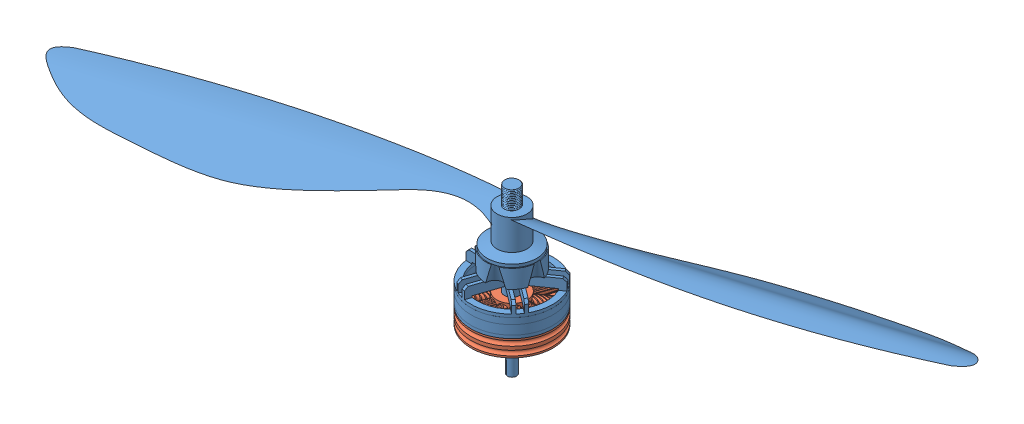
SolidWorks assembly Motordrone, configuration Predeterminado. Lengths in mm.
Overall size (2468.7 543.23 997.38).
2 component instances, 2 part files, 2 mates.
Components (placement in the parent):
- Motor drone-1: Motor drone [Predeterminado] at (-484.6905 198.3144 2500.6944) x (0.955281 0 -0.2957) z (0.2957 0 0.955281) size (2500.69 543.23 270)
- Pieza1-1: Pieza1 [Predeterminado] at (-484.6905 198.3144 2500.6944) x (-1 0 0) z (0 -1 0) size (270 270 95)
Mates (geometry in assembly coordinates):
- Concéntrica1: concentric anti-aligned: circle of Motor drone-1; circle of Pieza1-1
- Coincidente4: coincident anti-aligned: plane of Motor drone-1 through (-484.6905 198.3144 2500.6944) normal (0 -1 0); plane of Pieza1-1 through (-484.6905 198.3144 2500.6944) normal (0 1 0)
